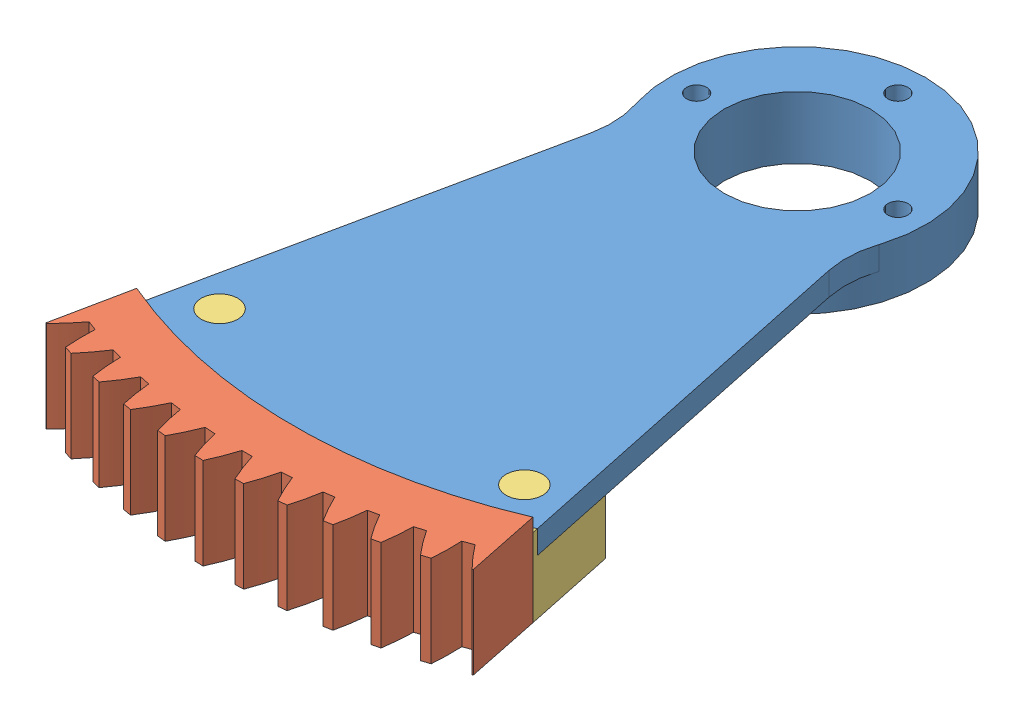
SolidWorks assembly Assem1, configuration Default. Lengths in mm.
Overall size (46.72 10 77.23).
4 component instances, 3 part files, 2 mates.
Components (placement in the parent):
- key_gear-1: key_gear [Default] at (36.0038 36.9066 16.8186) size (43.07 6.81 68.4)
- gear_attach2-1: gear_attach2 [Default] at (44.7478 39.0212 36.9912) x (0 -1 0) z (1 0 0) size (10 22.7 46.72)
  - Metric - Spur gear 1.375M 90T 20PA 10FW ---S90O75H50L110N-1: Metric - Spur gear 1.375M 90T 20PA 10FW ---S90O75H50L110N [Metric - Spur gear 1.375M 90T 20PA 10FW ---S90O75H50L110N] at (-1.8854 10.4513 -8.744) size (10 126.45 126.5)
  - 3d_extend-1: 3d_extend [Default] at (8.1146 10.4513 -8.744) x (0 0 1) z (-1 0 0) size (43.33 14.47 8.54)
Mates (geometry in assembly coordinates):
- Coincident6: coincident: circle of key_gear-1; circle of gear_attach2-1/3d_extend-1
- Coincident7: coincident aligned: circle of key_gear-1; circle of gear_attach2-1/3d_extend-1
